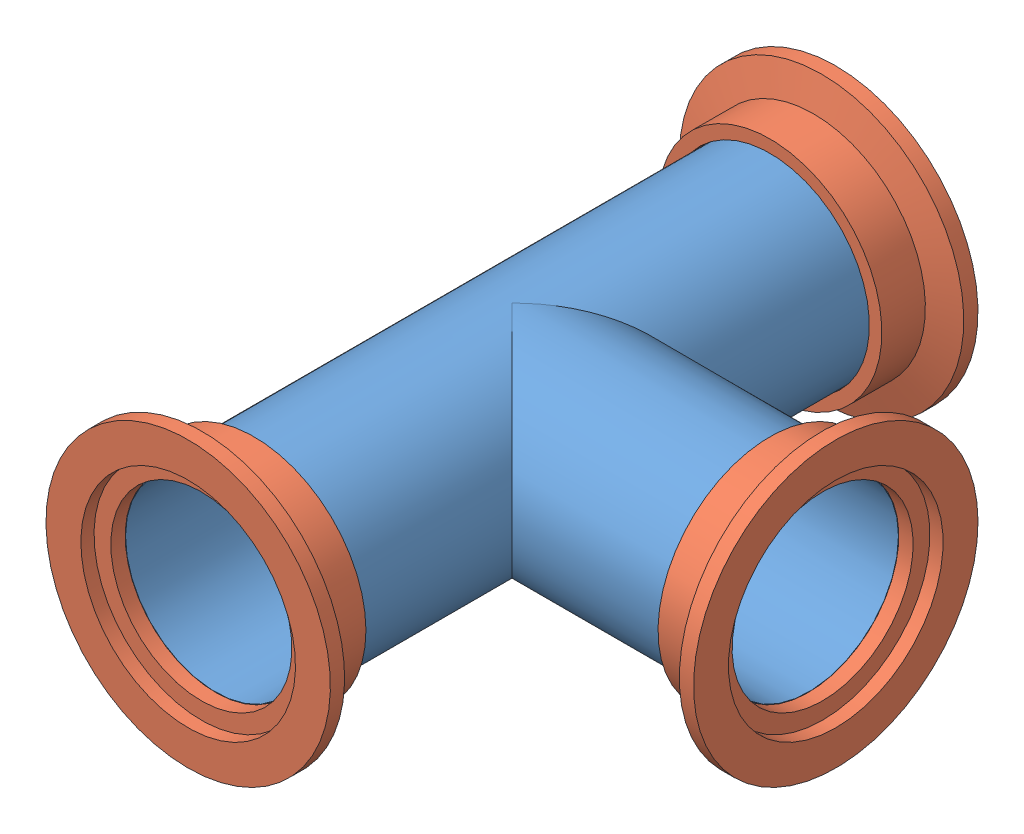
SolidWorks assembly 724002, configuration Default. Lengths in mm.
Overall size (94.19 67.56 124.92).
4 component instances, 2 part files, 6 mates.
Components (placement in the parent):
- 404502-1: 404502 [Default] at (31.3344 61.8244 82.183) size (76.2 38.1 114.3)
- 713003-99-1: 713003-99 [Default] at (31.3344 61.8244 144.6416) x (-0.985191 -0.171461 0) z (-0.171461 0.985191 0) size (54.86 12.7 54.86)
- 713003-99-2: 713003-99 [Default] at (93.793 61.8244 82.183) x (0 0.268037 -0.963408) z (0 -0.963408 -0.268037) size (54.86 12.7 54.86)
- 713003-99-3: 713003-99 [Default] at (31.3344 61.8244 19.7244) x (-0.081196 -0.996698 0) z (0.996698 -0.081196 0) size (54.86 12.7 54.86)
Mates (geometry in assembly coordinates):
- Concentric1: concentric: circle of 404502-1; circle of 713003-99-1
- Coincident1: coincident anti-aligned: plane of 404502-1 through (31.3344 61.8244 139.333) normal (0 0 1); plane of 713003-99-1 through (12.4414 58.5363 139.333) normal (0 0 -1)
- Concentric2: concentric: cylinder of 404502-1 through (12.2834 61.8244 82.183) axis (1 0 0) radius 19.05; cylinder of 713003-99-2 through (93.793 61.8244 82.183) axis (1 0 0) radius 19.177
- Coincident2: coincident anti-aligned: plane of 404502-1 through (88.4844 61.8244 82.183) normal (1 0 0); plane of 713003-99-2 through (88.4844 66.9646 63.7078) normal (-1 0 0)
- Concentric3: concentric: cylinder of 404502-1 through (31.3344 61.8244 139.333) axis (0 0 -1) radius 19.05; cylinder of 713003-99-3 through (31.3344 61.8244 -61.0052) axis (0 0 -1) radius 21.59
- Coincident3: coincident anti-aligned: plane of 404502-1 through (31.3344 61.8244 25.033) normal (0 0 -1); plane of 713003-99-3 through (29.7773 42.7107 25.033) normal (0 0 1)
